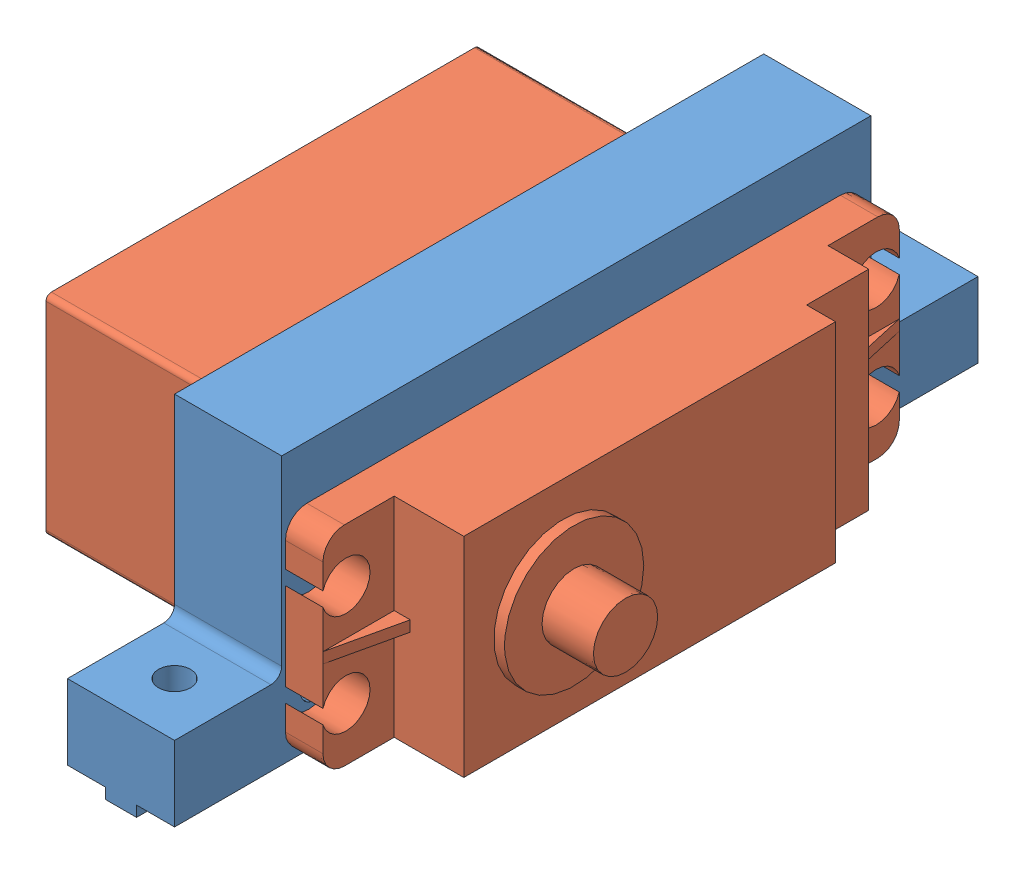
SolidWorks assembly FingerGrabber2020Assembly, configuration Default. Lengths in mm.
Overall size (44.8 26 75).
2 component instances, 2 part files, 3 mates.
Components (placement in the parent):
- MG996RMakerBeamSupport-1: MG996RMakerBeamSupport [Default] at (17.4992 30.3705 60.9123) size (10 26 75)
- MG996R-1: MG996R [Default] at (-6.5008 40.6205 40.9123) x (0 -1 0) z (0 0 1) size (19.5 44.8 53.8)
Mates (geometry in assembly coordinates):
- Coincident2: coincident: plane of MG996RMakerBeamSupport-1 through (22.4992 50.3705 81.4123) normal (0 -1 0); plane of MG996R-1 through (7.034 50.3705 81.4123) normal (0 1 0)
- Coincident3: coincident: plane of MG996RMakerBeamSupport-1 through (22.4992 50.3705 81.4123) normal (0 0 -1); plane of MG996R-1 through (36.034 30.8705 81.4123) normal (0 0 1)
- Coincident4: coincident anti-aligned: plane of MG996RMakerBeamSupport-1 through (22.4992 55.3705 98.4123) normal (1 0 0); plane of MG996R-1 through (22.4992 30.8705 88.0623) normal (-1 0 0)
